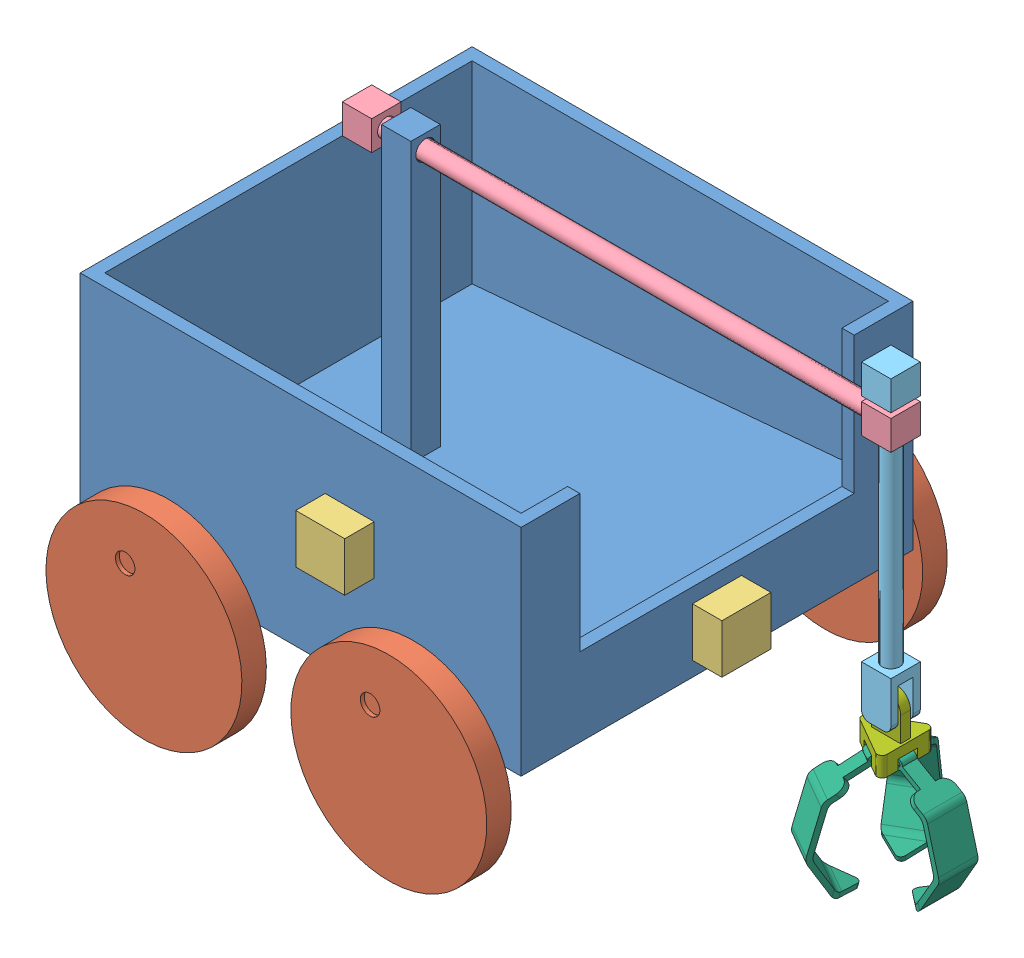
SolidWorks assembly BOT6, configuration Default. Lengths in mm.
Overall size (735.6 510.68 470).
14 component instances, 7 part files, 34 mates.
Components (placement in the parent):
- Base-1: Base [Default] at origin size (450 370 400)
- Wheel-1: Wheel [Default] at (125 -25 -235) size (200 200 105)
- Wheel-2: Wheel [Default] at (-125 -25 -235) size (200 200 105)
- Wheel-3: Wheel [Default] at (-125 -25 235) x (-0.923728 -0.383049 0) z (0 0 -1) size (200 200 105)
- Wheel-4: Wheel [Default] at (125 -25 235) x (-0.923728 -0.383049 0) z (0 0 -1) size (200 200 105)
- Camera-1: Camera [Default] at (50 125 230) x (0 0 -1) z (1 0 0) size (30 50 50)
- Camera-2: Camera [Default] at (50 125 -200) x (0 0 -1) z (1 0 0) size (30 50 50)
- Camera-3: Camera [Default] at (225 40 0) size (30 50 50)
- Extension Pole 1-1: Extension Pole 1 [Default] at (-142.5 305 0) size (560 30 30)
- Extension Pole 2-1: Extension Pole 2 [Default] at (402.5 355 0) x (-1 0 0) z (0 0 1) size (30 315 30)
- Angular Finger-1: Angular Finger [Default] at (399.1062 -46.3881 -5.8782) x (-0.482963 0.258819 -0.836516) z (0.866025 0 -0.5) size (54.05 118 40)
- Angular Finger-2: Angular Finger [Default] at (409.2875 -46.3881 0) x (0.965926 0.258819 0) z (0 0 1) size (54.05 118 40)
- Angular Finger-3: Angular Finger [Default] at (399.1062 -46.3881 5.8782) x (-0.482963 0.258819 0.836516) z (-0.866025 0 -0.5) size (54.05 118 40)
- Triangular Holder-1: Triangular Holder [Default] at (402.5 27.5 0) x (-1 0 0) z (0 0 -1) size (46.96 60 52.68)
Mates (geometry in assembly coordinates):
- Concentric1: concentric aligned: cylinder of Base-1 through (-125 -25 -132.5736) axis (0 0 -1) radius 15; cylinder of Wheel-2 through (-125 -25 -130) axis (0 0 -1) radius 14
- Distance1: distance = 10 mm anti-aligned: plane of Wheel-2 through (-125 -25 -210) normal (0 0 1); plane of Base-1 through (-225 220 -200) normal (0 0 -1)
- Concentric2: concentric aligned: cylinder of Base-1 through (-125 -25 132.5736) axis (0 0 1) radius 15; cylinder of Wheel-3 through (-125 -25 130) axis (0 0 1) radius 14
- Distance2: distance = 10 mm anti-aligned: plane of Base-1 through (-225 220 200) normal (0 0 1); plane of Wheel-3 through (-125 -25 210) normal (0 0 -1)
- Concentric5: concentric aligned: cylinder of Base-1 through (125 -25 132.5736) axis (0 0 1) radius 15; cylinder of Wheel-4 through (125 -25 130) axis (0 0 1) radius 14
- Distance4: distance = 10 mm anti-aligned: plane of Base-1 through (-225 220 200) normal (0 0 1); plane of Wheel-4 through (125 -25 210) normal (0 0 -1)
- Concentric6: concentric aligned: cylinder of Base-1 through (125 -25 -132.5736) axis (0 0 -1) radius 15; cylinder of Wheel-1 through (125 -25 -130) axis (0 0 -1) radius 14
- Distance5: distance = 10 mm anti-aligned: plane of Base-1 through (-225 220 -200) normal (0 0 -1); plane of Wheel-1 through (125 -25 -210) normal (0 0 1)
- Concentric7: concentric anti-aligned: cylinder of Base-1 through (-102.5 305 0) axis (1 0 0) radius 10; cylinder of Extension Pole 1-1 through (387.5 305 0) axis (-1 0 0) radius 9
- Concentric8: concentric aligned: cylinder of Extension Pole 1-1 through (402.5 261.7157 0) axis (0 1 0) radius 10; cylinder of Extension Pole 2-1 through (402.5 90 0) axis (0 1 0) radius 9
- Coincident5: coincident aligned: plane of Base-1 through (-102.5 320 15) normal (0 0 1); plane of Extension Pole 2-1 through (417.5 325 15) normal (0 0 1)
- Coincident6: coincident anti-aligned: plane of Base-1 through (225 220 -200) normal (1 0 0); plane of Camera-3 through (225 40 0) normal (-1 0 0)
- Distance6: distance = 15 mm aligned: plane of Camera-3 through (255 15 25) normal (0 -1 0); plane of Base-1 through (0 0 0) normal (0 -1 0)
- Distance7: distance = 175 mm aligned: plane of Camera-3 through (255 65 -25) normal (0 0 -1); plane of Base-1 through (-225 220 -200) normal (0 0 -1)
- Coincident9: coincident anti-aligned: plane of Base-1 through (-225 220 200) normal (0 0 1); plane of Camera-1 through (50 125 200) normal (0 0 -1)
- Distance8: distance = 100 mm aligned: plane of Camera-1 through (75 100 200) normal (0 -1 0); plane of Base-1 through (0 0 0) normal (0 -1 0)
- Distance9: distance = 150 mm aligned: plane of Camera-1 through (75 150 200) normal (1 0 0); plane of Base-1 through (225 220 -200) normal (1 0 0)
- Coincident12: coincident anti-aligned: plane of Base-1 through (-225 220 -200) normal (0 0 -1); plane of Camera-2 through (50 125 -200) normal (0 0 1)
- Distance10: distance = 100 mm aligned: plane of Camera-2 through (75 100 -230) normal (0 -1 0); plane of Base-1 through (0 0 0) normal (0 -1 0)
- Distance11: distance = 150 mm aligned: plane of Base-1 through (225 220 -200) normal (1 0 0); plane of Camera-2 through (75 150 -230) normal (1 0 0)
- LimitDistance2: limit distance = 10 mm anti-aligned: plane of Extension Pole 1-1 through (-112.5 305 0) normal (1 0 0); plane of Base-1 through (-102.5 320 -15) normal (-1 0 0)
- LimitDistance3: limit distance = 5 mm anti-aligned: plane of Extension Pole 1-1 through (417.5 320 15) normal (0 1 0); plane of Extension Pole 2-1 through (402.5 325 0) normal (0 -1 0)
- Concentric9: concentric anti-aligned: cylinder of Angular Finger-3 through (378.0192 10.5 2.4019) axis (0.866025 0 0.5) radius 2.5; cylinder of Triangular Holder-1 through (407.6742 10.5 19.5232) axis (-0.866025 0 -0.5) radius 1.5
- Distance12: distance = 2.5 mm anti-aligned: plane of Triangular Holder-1 through (411.1603 17.5 5) normal (-0.866025 0 -0.5); plane of Angular Finger-3 through (405.6014 -46.3881 9.6282) normal (0.866025 0 0.5)
- Concentric10: concentric anti-aligned: cylinder of Angular Finger-1 through (412.6603 10.5 -22.4019) axis (-0.866025 0 0.5) radius 2.5; cylinder of Triangular Holder-1 through (383.0053 10.5 -5.2806) axis (0.866025 0 -0.5) radius 1.5
- Distance13: distance = 2.5 mm anti-aligned: plane of Triangular Holder-1 through (385.1795 17.5 -10) normal (0.866025 0 -0.5); plane of Angular Finger-1 through (392.611 -46.3881 -2.1282) normal (-0.866025 0 0.5)
- Concentric11: concentric anti-aligned: cylinder of Angular Finger-2 through (416.8205 10.5 20) axis (0 0 -1) radius 2.5; cylinder of Triangular Holder-1 through (416.8205 10.5 -14.2426) axis (0 0 1) radius 1.5
- Distance14: distance = 2.5 mm anti-aligned: plane of Triangular Holder-1 through (402.5 17.5 10) normal (0 0 -1); plane of Angular Finger-2 through (409.2875 -46.3881 7.5) normal (0 0 1)
- LimitAngle2: limit planar angle = 2.094395 rad anti-aligned: plane of Triangular Holder-1 through (419.8205 7.5 -30) normal (-0.5 0 -0.866025); plane of Angular Finger-1 through (402.5435 1.7049 -39.9247) normal (-0.25 0.866025 -0.433013)
- LimitAngle3: limit planar angle = 2.094395 rad anti-aligned: plane of Triangular Holder-1 through (419.8205 7.5 30) normal (1 0 0); plane of Angular Finger-2 through (437.0541 1.7049 20) normal (0.5 0.866025 0)
- LimitAngle4: limit planar angle = 2.094395 rad anti-aligned: plane of Triangular Holder-1 through (367.859 7.5 0) normal (-0.5 0 0.866025); plane of Angular Finger-3 through (367.9025 1.7049 19.9247) normal (-0.25 0.866025 0.433013)
- Concentric12: concentric anti-aligned: cylinder of Extension Pole 2-1 through (402.5 52.5 -28.7132) axis (0 0 1) radius 7.5; cylinder of Triangular Holder-1 through (402.5 52.5 27.6274) axis (0 0 -1) radius 8
- Distance16: distance = 2.5 mm anti-aligned: plane of Triangular Holder-1 through (417.5 67.5 -5) normal (0 0 -1); plane of Extension Pole 2-1 through (417.5 80 -7.5) normal (0 0 1)
- LimitAngle5: limit planar angle = 1.570796 rad anti-aligned: plane of Triangular Holder-1 through (402.5 27.5 0) normal (0 1 0); plane of Extension Pole 2-1 through (417.5 40 -15) normal (1 0 0)
